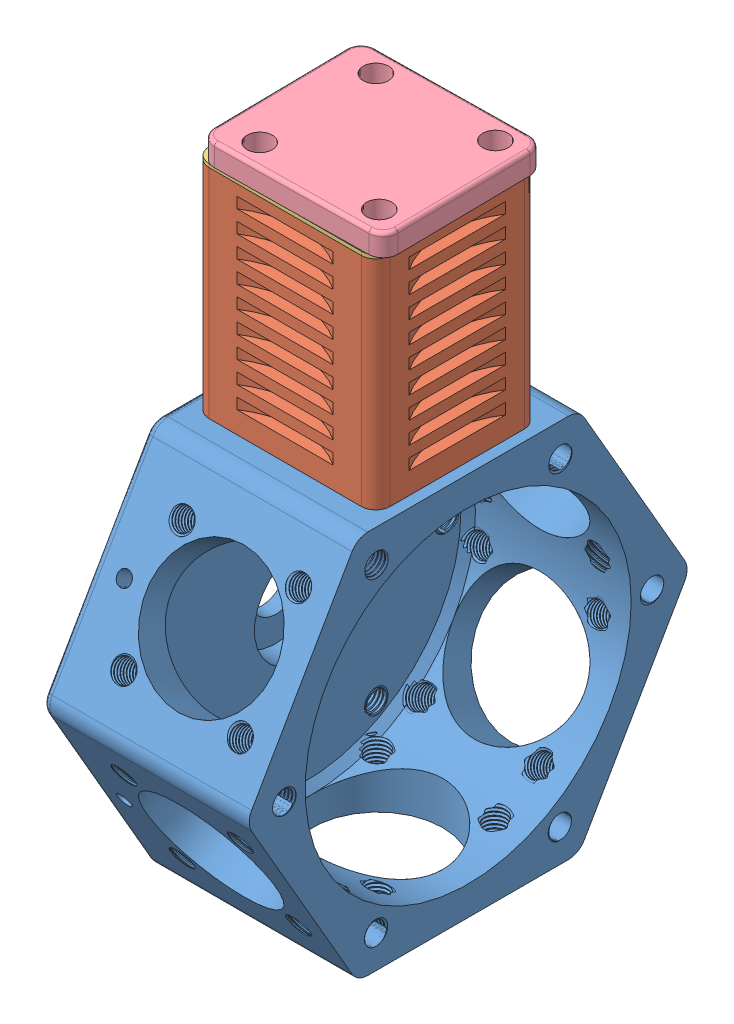
SolidWorks assembly Assembly, configuration Default. Lengths in mm.
Overall size (58.31 173.38 120.85).
4 component instances, 4 part files, 8 mates.
Components (placement in the parent):
- Crankcase-1: Crankcase [Default] at (40.1799 67.5464 92.3221) size (58.31 106.76 120.85)
- Cylinder-1: Cylinder [Default] at (40.6799 120.5464 92.3221) size (50 62 45)
- Cylinder Head Gasket-2: Cylinder Head Gasket [Default] at (40.6799 180.5464 92.3221) x (-1 0 0) z (0 0 -1) size (50 1 45)
- Cylinder Head-1: Cylinder Head [Default] at (42.18 181.5464 92.3433) x (-0.9999 0 0.014115) z (-0.014115 0 -0.9999) size (50 7 45)
Mates (geometry in assembly coordinates):
- Coincident4: coincident anti-aligned: plane of Crankcase-1 through (11.6799 120.5464 64.6093) normal (0 1 0); plane of Cylinder-1 through (61.6799 120.5464 73.8221) normal (0 -1 0)
- Concentric4: concentric anti-aligned: cylinder of Crankcase-1 through (43.6799 14.5454 92.3221) axis (0 1 0) radius 18; cylinder of Cylinder-1 through (43.6799 180.5464 92.3221) axis (0 -1 0) radius 16
- Parallel4: parallel aligned: plane of Crankcase-1 through (68.6799 19.5464 120.0349) normal (1 0 0); plane of Cylinder-1 through (65.6799 180.5464 110.8221) normal (1 0 0)
- Concentric5: concentric aligned: cylinder of Cylinder-1 through (43.6799 180.5464 92.3221) axis (0 -1 0) radius 16; cylinder of Cylinder Head Gasket-2 through (43.6799 181.5464 92.3221) axis (0 -1 0) radius 18
- Coincident9: coincident anti-aligned: plane of Cylinder-1 through (61.6799 180.5464 73.8221) normal (0 1 0); plane of Cylinder Head Gasket-2 through (61.6799 180.5464 73.8221) normal (0 -1 0)
- Coincident10: coincident aligned: plane of Cylinder-1 through (65.6799 180.5464 110.8221) normal (1 0 0); plane of Cylinder Head Gasket-2 through (65.6799 181.5464 73.8221) normal (1 0 0)
- Concentric6: concentric anti-aligned: cylinder of Cylinder-1 through (43.6799 180.5464 92.3221) axis (0 -1 0) radius 16; cylinder of Cylinder Head-1 through (43.6799 181.0464 92.3221) axis (0 1 0) radius 16
- Coincident11: coincident anti-aligned: plane of Cylinder Head Gasket-2 through (61.6799 181.5464 73.8221) normal (0 1 0); plane of Cylinder Head-1 through (20.921 181.5464 74.1415) normal (0 -1 0)
